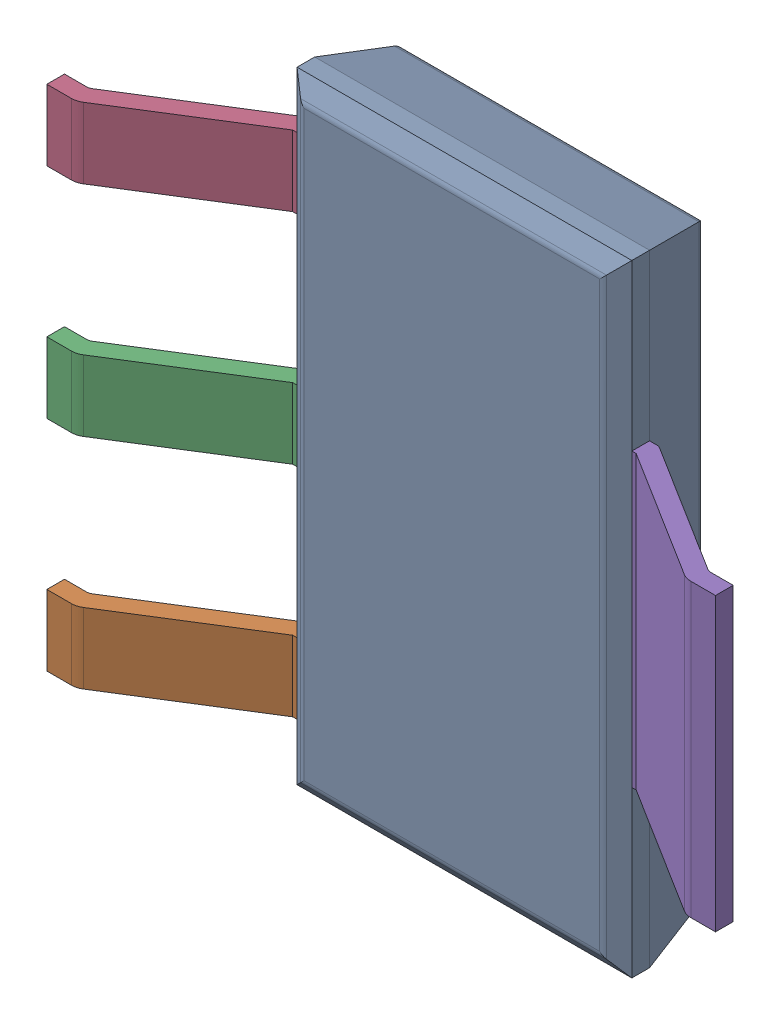
SolidWorks assembly IC1_4.step, configuration Default. Lengths in mm.
Overall size (7 6.51 1.8).
4 component instances, 3 part files, 0 mates.
Components (placement in the parent):
- 6383673440.step-1: 6383673440.step [Default] at (120.094 106.807 -1.1227) x (1 0 0) z (0 0 -1) size (7 6.51 1.8)
  - Body_9.step-5: Body_9.step [Default] at origin size (3.5 6.51 1.06)
  - PinsArrayL_3.step-5: PinsArrayL_3.step [Default] at origin size (1.75 5.32 1.06)
  - FilletPinR_3.step-5: FilletPinR_3.step [Default] at origin size (1.75 3.05 1.06)
